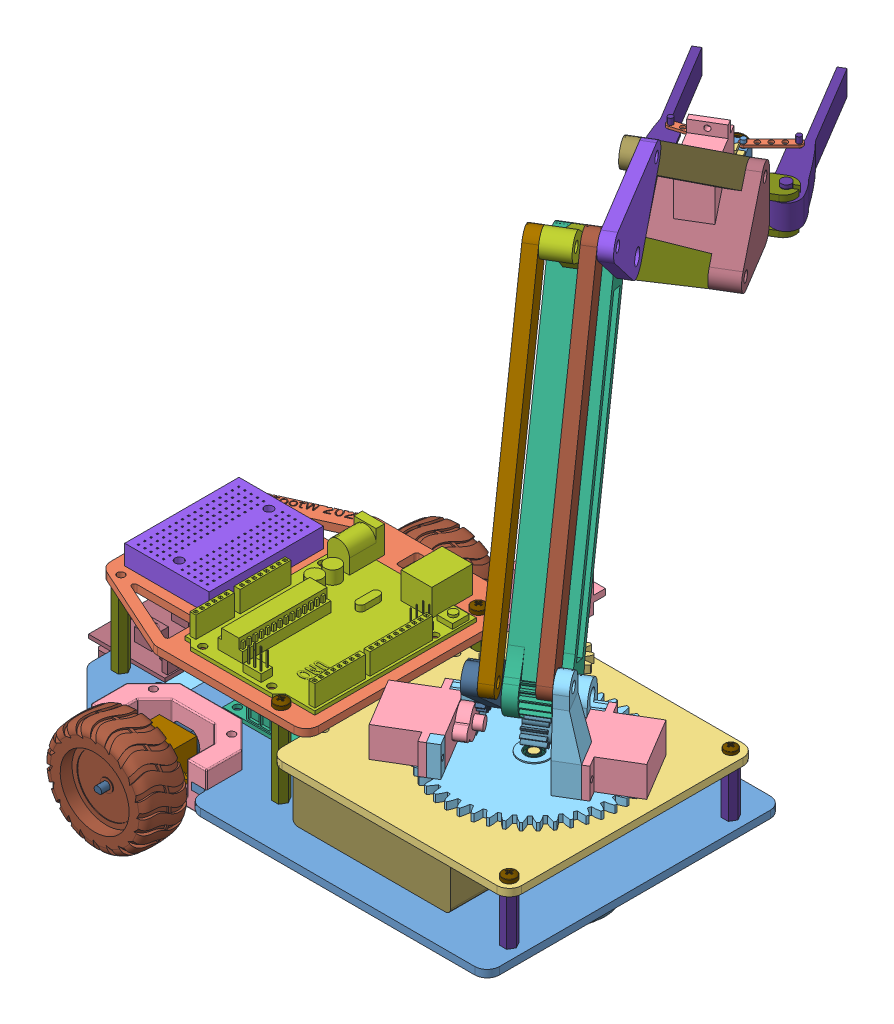
SolidWorks assembly Excavator, configuration Default. Lengths in mm.
Overall size (236.8 214.82 343.47).
64 component instances, 39 part files, 3 mates.
Components (placement in the parent):
- Vehicle Body-1: Vehicle Body [Default] at origin size (199.9 82.83 154.81)
  - Main Deck-1: Main Deck [Default] at origin size (190 3 120)
  - Electrical Control Deck-1: Electrical Control Deck [Default] at origin size (100 3 90)
  - Robotic Deck-2: Robotic Deck [No Robotic] at origin size (103.88 48 106.79)
  - Motor Holder Holder-1: Motor Holder Holder [Default] at origin size (47.05 17 25.5)
  - Track Sensor Holder-1: Track Sensor Holder [Default] at origin size (30 6 57)
  - L298N-1: L298N [Default] at (87.0626 3 -21.5) x (-1 0 0) z (0 0 -1) size (43 26.5 43)
  - Arduino Uno-1: Arduino Uno [預設] at (60.6 36 11.8481) x (0 0 1) z (-1 0 0) size (75.5 12.5 52.7)
  - Breadboard-1: Breadboard [Default] at (23.1667 36 0) x (0 0 -1) z (1 0 0) size (46.4 8 34.3)
  - Motor Holder-5: Motor Holder [Default] at (45 6.5 40.5) size (25 11.6 12)
  - GA12-N20-1: GA12-N20 [Default] at (45 1.5 38.5) x (-1 0 0) z (0 0 1) size (12 10 36.1)
  - Tire-1: Tire [Default] at (45 1.5 63.35) x (1 0 0) z (0 0 -1) size (46.07 46.07 24)
  - Battery Holder-1: Battery Holder [預設] at (97.9058 21 46.784) x (1 0 0) z (0 0 -1) size (64 18 70)
  - Tire-2: Tire [Default] at (45 1.5 -67.459) x (1 0 0) z (0 0 -1) size (46.07 46.07 24)
  - GA12-N20-2: GA12-N20 [Default] at (45 1.5 -38.5) x (1 0 0) z (0 0 -1) size (12 10 36.1)
  - Trace Sensor-1: Trace Sensor [Default] at (-9.8952 1.9682 0) size (35.43 17 14)
  - Roller-1: Roller [Default] at (166 0 0) x (0 0 -1) z (-1 0 0) size (49 20 32)
  - PP3 Battery-1: PP3 Battery [預設] at (154.0774 19.5 -49.616) x (0 0 1) z (0 -1 0) size (26.4 49.1 16.5)
  - Hexagon Brass Cylinder 30mm-1: Hexagon Brass Cylinder 30mm [Default] at (8.3674 33 27.0854) x (1 0 0) z (0 0 -1) size (5.77 35 5)
  - Hexagon Brass Cylinder 30mm-5: Hexagon Brass Cylinder 30mm [Default] at (86.6598 33 40.308) x (-1 0 0) z (0 0 1) size (5.77 35 5)
  - Hexagon Brass Cylinder 30mm-6: Hexagon Brass Cylinder 30mm [Default] at (93.3054 33 -33.2195) x (-0.866025 0 -0.5) z (-0.5 0 0.866025) size (5.77 35 5)
  - Hexagon Brass Cylinder 30mm-7: Hexagon Brass Cylinder 30mm [Default] at (16.3794 33 -26.6064) x (-1 0 0) z (0 0 1) size (5.77 35 5)
  - Hexagon Brass Cylinder 20mm-1: Hexagon Brass Cylinder 20mm [Default] at (94 23 -23.2195) x (-1 0 0) z (0 0 1) size (5.77 25 5)
  - Hexagon Brass Cylinder 20mm-2: Hexagon Brass Cylinder 20mm [Default] at (184 23 45) x (-1 0 0) z (0 0 1) size (5.77 25 5)
  - Hexagon Brass Cylinder 20mm-3: Hexagon Brass Cylinder 20mm [Default] at (184 23 -45) x (-1 0 0) z (0 0 1) size (5.77 25 5)
  - Hexagon Brass Cylinder 20mm-4: Hexagon Brass Cylinder 20mm [Default] at (94 23 30.308) x (-1 0 0) z (0 0 1) size (5.77 25 5)
  - Trace Sensor-4: Trace Sensor [Default] at (-9.8952 1.9682 -15) size (35.43 17 14)
  - Trace Sensor-5: Trace Sensor [Default] at (-9.8952 1.9682 15) size (35.43 17 14)
  - Motor Holder-6: Motor Holder [Default] at (45 6.5 -40.5) x (-1 0 0) z (0 0 -1) size (25 11.6 12)
  - pan head cross recess screw_iso-4: pan head cross recess screw_iso [ISO 7045 - M3 x 8 - Z - 8N] at (86.6598 38.4 40.308) x (0 -1 0) z (-0.31572 0 0.948852) size (10.35 5.6 5.6)
  - pan head cross recess screw_iso-6: pan head cross recess screw_iso [ISO 7045 - M3 x 8 - Z - 8N] at (93.3054 38.4 -33.2195) x (0 -1 0) z (0 0 1) size (10.35 5.6 5.6)
  - pan head cross recess screw_iso-8: pan head cross recess screw_iso [ISO 7045 - M3 x 8 - Z - 8N] at (184 28.4 45) x (0 -1 0) z (0 0 1) size (10.35 5.6 5.6)
  - pan head cross recess screw_iso-9: pan head cross recess screw_iso [ISO 7045 - M2.5 x 3 - Z - 3N] at (184 28.1 -45) x (0 -1 0) z (0 0 1) size (5.05 5 5)
  - hex nut style 1 gradeab_iso-3: hex nut style 1 gradeab_iso [ISO - 4032 - M3 - W - N] at (86.6598 -2.4 40.308) x (1 0 0) z (0 -1 0) size (5.5 6.35 2.4)
  - Motor Holder Holder-2: Motor Holder Holder [Default] at (90 0 0) x (-1 0 0) z (0 0 -1) size (47.05 17 25.5)
  - thrust ball bearing_68_iso-1: thrust ball bearing_68_iso [ISO 104 - 700412 - B,10,SI,NC,10_68] at (149 25 0) x (0 -1 0) z (0 0 1) size (4 12 12)
  - Motor Gear Base-1: Motor Gear Base [Default] at (131.7001 33.149 -44.9036) x (0 -1 0) z (0 0 1) size (7 32.71 32.71)
  - SG90-1: SG90 [預設] at (121.2224 43.2 -40.5922) x (-0.001269 0 0.999999) z (-0.999999 0 -0.001269) size (32.4 30 12.3)
- Robotic Arm-1: Robotic Arm [Default] at (169.5856 27.5 34.2963) x (0.51464 0 0.857406) z (-0.857406 0 0.51464) size (323.25 166.29 82.16)
  - Base-1: Base [Default] at origin size (70.44 42.78 70.48)
  - Linkage A-1: Linkage A [Default] at origin size (68.37 134.99 20)
  - Linkage B-1: Linkage B [Default] at origin size (170.74 129 10)
  - Linkage Triangle-1: Linkage Triangle [Default] at origin size (55.96 31.28 5)
  - Linkage C-1: Linkage C [Default] at origin size (62.37 128.99 5)
  - Linkage D-1: Linkage D [Default] at origin size (45.87 37.52 8)
  - Linkage E-1: Linkage E [Default] at origin size (62.37 128.99 5)
  - Linkage F-1: Linkage F [Default] at origin size (138.59 105.2 5)
  - End Effector Holder-1: End Effector Holder [Default] at origin size (32.98 29.28 30)
  - SG90-1: SG90 [預設] at (-36.2958 15.3 -19.0839) x (-1 0 0) z (0 -1 0) size (32.4 30 12.3)
  - Motor Gear A-1: Motor Gear A [Default] at (-51.6415 7.1728 -24.6402) x (0 0 1) z (-0.29407 -0.955784 0) size (14 9.19 9.6)
  - angular contact ball bearing_68_iso-1: angular contact ball bearing_68_iso [ISO 15 ABB - 274 - 14,SI,NC,14_68] at (-40 2.25 0) x (0 1 0) z (-0.034518 0 0.999404) size (2.5 7 7)
  - SG90-3: SG90 [預設] at (-36.2958 3 26.8766) x (-1 0 0) z (0 1 0) size (32.4 30 12.3)
  - 合成-1: 合成 [默认] at (-265.7385 -5.7178 1.85) x (0 0 -1) z (0 1 0) size (53.34 90.56 42.69)
    - 5-1: 5 [默认] at (-0.3901 -1.7944 50) size (50 10 15)
    - 3-1: 3 [默认] at (-5.0374 20.6698 50.1) x (0.999998 0.002089 0) z (0 0 1) size (10.94 69.45 18)
    - 2-1: 2 [默认] at (-0.3901 6.7056 50) x (-0.996573 0 0.082713) z (0 1 0) size (11.07 11.07 27.57)
    - 1-2: 1 [默认] at (-0.3901 13.4373 50) x (1 0 0) z (0 1 0) size (11.34 16 8.59)
    - 7-11: 7 [默认] at (-19.4053 21.3458 43.6) x (-0.244287 -0.969703 0) z (0 0 1) size (3 19 1)
    - 7-15: 7 [默认] at (-3.8901 17.4373 55.6) x (0.244287 0.969703 0) z (0 0 1) size (3 19 1)
    - 3-4: 3 [默认] at (4.2572 20.6698 50.1) x (-0.999998 0.002089 0) z (0 0 -1) size (10.94 69.45 18)
    - 7-16: 7 [默认] at (3.1099 17.4373 43.6) x (0.244287 -0.969703 0) z (0 0 1) size (3 19 1)
    - 7-17: 7 [默认] at (3.1099 17.4373 55.6) x (0.244287 -0.969703 0) z (0 0 1) size (3 19 1)
    - SG90-5: SG90 [預設] at (6.15 -10.1944 67.5937) x (0 0 -1) z (-1 0 0) size (32.4 30 12.3)
    - 4-3: 4 [默认] at (0 -2.2944 61.9937) x (0.999107 0 -0.04225) z (0 1 0) size (16.4 16.4 4)
Mates (geometry in assembly coordinates):
- Coincident5: coordinate: point of Car Body-1
- Concentric1: concentric aligned: circle of Vehicle Body-1/Robotic Deck-2; circle of Robotic Arm-1/Base-1
- Coincident6: coincident anti-aligned: plane of Vehicle Body-1/thrust ball bearing_68_iso-1 through (151.3 27 0) normal (0 1 0); plane of Robotic Arm-1/Base-1 through (149 27 0) normal (0 -1 0)
